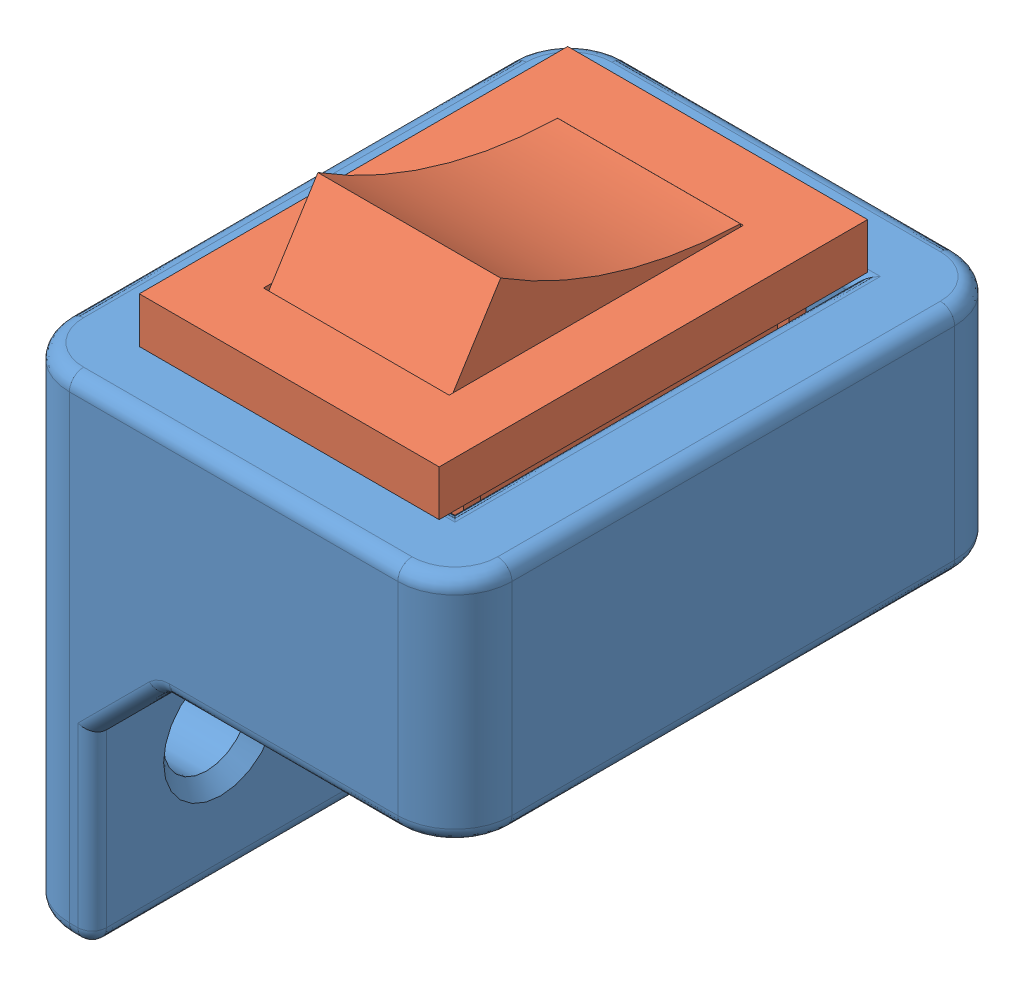
SolidWorks assembly Montagem Suporte Main Switch, configuration Valor predeterminado. Lengths in mm.
Overall size (15.5 21.3 19.5).
2 component instances, 2 part files, 4 mates.
Components (placement in the parent):
- Suporte Switch-1: Suporte Switch [Valor predeterminado] at origin size (15.5 17.1 19.5)
- tugas uts rocker switch-1: tugas uts rocker switch [Default] at (-0.15 4.05 0.15) x (0 0 -1) z (1 0 0) size (15 12.3 10.5)
Mates (geometry in assembly coordinates):
- Coincident1: coordinate: point of Suporte Switch-1
- Distance2: distance = 0.2 mm anti-aligned: plane of tugas uts rocker switch-1 through (-4.75 4.05 0.15) normal (-1 0 0); plane of Suporte Switch-1 through (-4.95 4.05 -6.95) normal (1 0 0)
- Distance1: distance = 0.2 mm anti-aligned: plane of tugas uts rocker switch-1 through (-4.35 -4.05 6.75) normal (0 0 1); plane of Suporte Switch-1 through (-4.95 4.05 6.95) normal (0 0 -1)
- Coincident4: coincident anti-aligned: plane of Suporte Switch-1 through (0 4.05 0) normal (0 1 0); plane of tugas uts rocker switch-1 through (-0.15 4.05 0.15) normal (0 -1 0)
